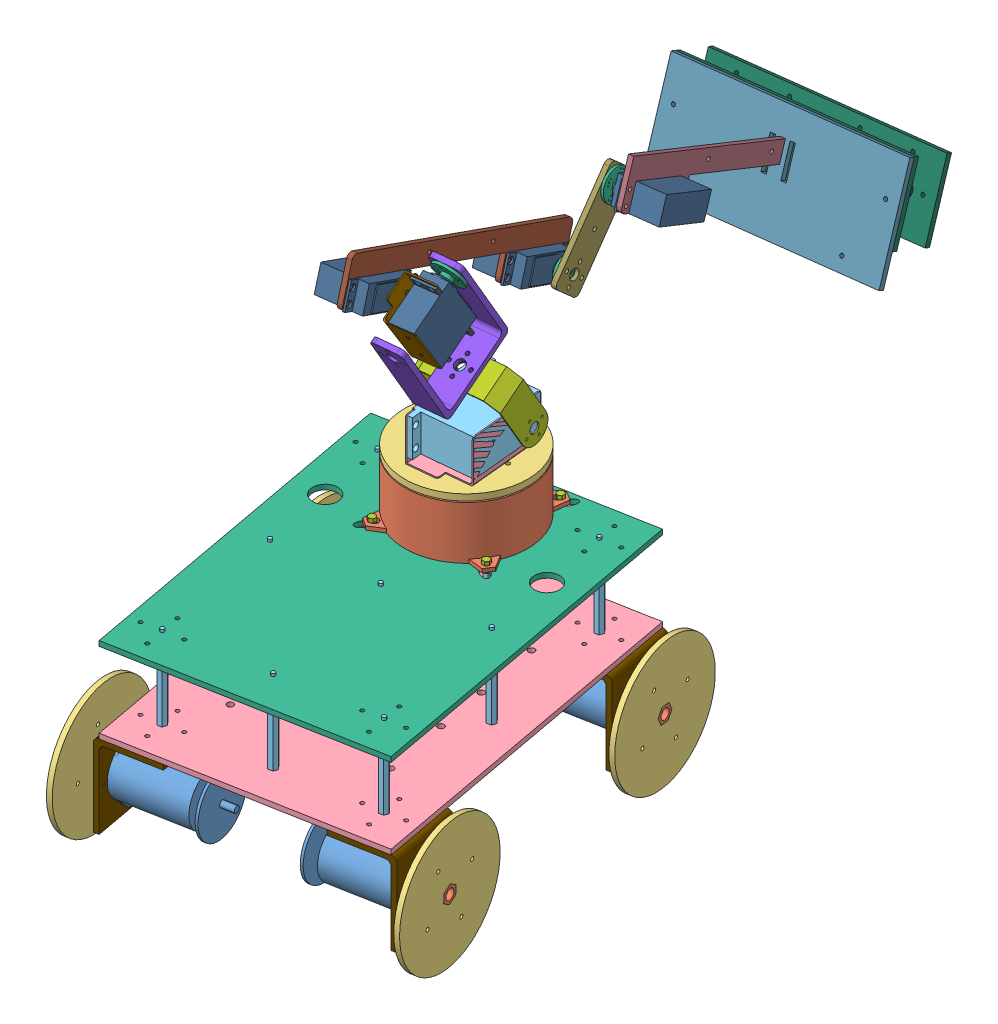
SolidWorks assembly arm 6 DOF + base 1, configuration Default. Lengths in mm.
Overall size (299.4 371.14 566.97).
57 component instances, 25 part files, 169 mates.
Components (placement in the parent):
- hs-422_sws-1: hs-422_sws [Default] at (6.6782 32.5822 43.0057) size (19.81 42.14 58.23)
- base arm-1: base arm [Default] at (19.6982 18.9554 48.4147) x (0.538087 0 -0.842889) z (0.842889 0 0.538087) size (118.01 42 118.01)
- arm base up-1: arm base up [Default] at (19.1744 54.8067 79.8171) x (0.097193 0 0.995266) z (0 1 0) size (98 98 12)
- hs 755 bracket-1: hs 755 bracket [Default] at (-18.8464 89.2206 93.9287) x (-0.995266 0 0.097193) z (-0.097193 0 -0.995266) size (44 34 74)
- hitec hs 755-1: hitec hs 755 [Default] at (45.4604 123.9367 40.3238) x (0 1 0) z (-0.995266 0 0.097193) size (29 74 56.99)
- servo bracket general-1: servo bracket general [Default] at (-12.6703 32.0195 41.7078) x (-0.004258 -0.99904 -0.043598) z (0.995266 0 -0.097193) size (24 24 6)
- u braket joint 1-2-1: u braket joint 1-2 [Default] at (33.276 118.3358 46.1876) x (0.995266 0 -0.097193) z (0.08298 -0.520656 0.849724) size (66 59 24)
- arm junc 2-1: arm junc 2 [Default] at (12.6131 149.17 90.5742) x (0.08298 -0.520656 0.849724) z (0.995266 0 -0.097193) size (64 79 24)
- bracket general hs 645-1: bracket general hs 645 [Default] at (16.6488 206.5636 80.7902) x (-0.08298 0.520656 -0.849724) z (0.016697 -0.851819 -0.52357) size (34 24 57)
- hitec hs 645-1: hitec hs 645 [Default] at (39.0641 204.9316 132.0518) x (-0.016697 0.851819 0.52357) z (-0.08298 0.520656 -0.849724) size (53.34 19.56 42.35)
- servo bracket general-2: servo bracket general [Default] at (69.3008 188.4841 66.8223) x (0.995803 0.010283 -0.090944) z (0.08298 -0.520656 0.849724) size (24 24 6)
- hitec hs 645-2: hitec hs 645 [Default] at (-35.8785 170.8154 49.8227) x (-0.03769 -0.353649 -0.934619) z (0.996411 0.057634 -0.06199) size (53.34 19.56 42.35)
- servo bracket general-3: servo bracket general [Default] at (14.8927 146.1475 127.4607) x (0.084071 -0.588853 0.803856) z (-0.996411 -0.057634 0.06199) size (24 24 6)
- juct c 2 joint-1: juct c 2 joint [Default] at (-16.5608 105.9929 -69.7374) x (-0.03769 -0.353649 -0.934619) z (0.996411 0.057634 -0.06199) size (196.25 35 4)
- hitec hs 645-3: hitec hs 645 [Default] at (-41.1788 121.0832 -81.6089) x (-0.03769 -0.353649 -0.934619) z (0.996411 0.057634 -0.06199) size (53.34 19.56 42.35)
- servo bracket general-4: servo bracket general [Default] at (5.0293 97.459 -76.3462) x (-0.007252 -0.671549 -0.740925) z (-0.996411 -0.057634 0.06199) size (24 24 6)
- arm junct hole 2-1: arm junct hole 2 [Default] at (4.0721 173.6444 -20.9013) x (0.008166 0.6635 0.748131) z (0.996411 0.057634 -0.06199) size (24 80 4)
- hitec hs 645-4: hitec hs 645 [Default] at (49.3983 199.8468 -45.1922) x (0.034818 0.38846 0.920807) z (-0.996411 -0.057634 0.06199) size (53.34 19.56 42.35)
- servo bracket general-5: servo bracket general [Default] at (8.842 133.2278 -46.3345) x (0.083345 -0.795839 0.599745) z (0.996411 0.057634 -0.06199) size (24 24 6)
- juct c 1 joint-1: juct c 1 joint [Default] at (27.8754 177.4322 -42.184) x (0.034818 0.38846 0.920807) z (-0.996411 -0.057634 0.06199) size (140.63 35 4)
- base effector-2: base effector [Default] at (15.0512 145.8778 -201.8232) x (0.996411 0.057634 -0.06199) z (0.034818 0.38846 0.920807) size (180 80 4)
- base webcam fix-1: base webcam fix [Default] at (36.5081 139.2518 -204.1832) x (-0.996411 -0.057634 0.06199) z (-0.034818 -0.38846 -0.920807) size (180 57 4)
- base GM-1: base GM [Default] at (61.7595 88.9126 -188.5139) x (0.996411 0.057634 -0.06199) z (-0.077151 0.919661 -0.38506) size (128 34 20)
- webcam sturdy-2: webcam sturdy [Default] at (35.3697 136.1831 -213.1626) x (-0.996411 -0.057634 0.06199) z (-0.034818 -0.38846 -0.920807) size (79 27 33.5)
- webcam sturdy-3: webcam sturdy [Default] at (-51.318 131.1689 -207.7694) x (-0.996411 -0.057634 0.06199) z (-0.034818 -0.38846 -0.920807) size (79 27 33.5)
- base webcam fix-4: base webcam fix [Default] at (-0.8454 120.559 -226.9219) x (0.996411 0.057634 -0.06199) z (-0.034818 -0.38846 -0.920807) size (180 57 4)
- base junc motor-1: base junc motor [Default] at (-59.8759 -62.795 45.0091) x (0.983449 0 -0.181186) z (0.181186 0 0.983449) size (48 66 56)
- motor dc 1 NISCA-1: motor dc 1 NISCA [Default] at (-81.5979 -135.4054 72.2952) x (0 -1 0) z (0.983449 0 -0.181186) size (54 48 92)
- shaft adapter motor-1: shaft adapter motor [Default] at (-87.0776 -117.0125 64.6288) x (0.115247 -0.771631 0.625543) z (-0.983449 0 0.181186) size (12 13.86 17)
- wheel-1: wheel [Default] at (-110.9174 -68.6438 6.9798) x (-0.178701 -0.165038 -0.969963) z (-0.983449 0 0.181186) size (100 100 4)
- base junc motor-5: base junc motor [Default] at (85.0721 -62.795 18.3046) x (-0.983449 0 0.181186) z (-0.181186 0 -0.983449) size (48 66 56)
- motor dc 1 NISCA-5: motor dc 1 NISCA [Default] at (115.0919 -46.9812 36.058) x (0 1 0) z (-0.983449 0 0.181186) size (54 48 92)
- shaft adapter motor-5: shaft adapter motor [Default] at (111.0741 -111.9911 -7.8266) x (-0.149618 -0.564004 -0.812105) z (0.983449 0 -0.181186) size (12 13.86 17)
- wheel-5: wheel [Default] at (118.4063 -99.8622 -39.7783) x (-0.163308 0.433138 -0.88641) z (0.983449 0 -0.181186) size (100 100 4)
- base junc motor-7: base junc motor [Default] at (123.8459 -62.795 228.7626) x (-0.983449 0 0.181186) z (-0.181186 0 -0.983449) size (48 66 56)
- motor dc 1 NISCA-7: motor dc 1 NISCA [Default] at (145.5678 -135.4054 201.4765) x (0 -1 0) z (-0.983449 0 0.181186) size (54 48 92)
- shaft adapter motor-7: shaft adapter motor [Default] at (149.9905 -69.6302 203.4055) x (-0.097948 0.841282 -0.531649) z (0.983449 0 -0.181186) size (12 13.86 17)
- wheel-7: wheel [Default] at (162.0366 -115.058 174.9636) x (-0.083033 -0.888811 -0.450689) z (-0.983449 0 0.181186) size (100 100 4)
- base junc motor-8: base junc motor [Default] at (-21.1022 -62.795 255.4672) x (0.983449 0 -0.181186) z (0.181186 0 0.983449) size (48 66 56)
- shaft adapter motor-8: shaft adapter motor [Default] at (-45.9025 -101.6896 288.1209) x (0.178209 -0.180542 0.967288) z (-0.983449 0 0.181186) size (12 13.86 17)
- motor dc 1 NISCA-8: motor dc 1 NISCA [Default] at (-51.1219 -46.9812 237.7137) x (0 1 0) z (0.983449 0 -0.181186) size (54 48 92)
- wheel-9: wheel [Default] at (-76.1406 -113.0058 217.8192) x (-0.178209 0.180542 -0.967288) z (0.983449 0 -0.181186) size (100 100 4)
- base odroid down fix-2: base odroid down fix [Default] at (34.2802 -56.1933 60.301) x (0.181186 0 0.983449) z (0 1 0) size (270 200 4)
- spacer 6cm-10: spacer 6cm [Default] at (127.024 7.8067 228.5274) x (0.942285 0 0.334813) z (0 -1 0) size (6 6.93 72)
- spacer 6cm-11: spacer 6cm [Default] at (52.2819 7.8067 242.2975) x (0.942285 0 0.334813) z (0 -1 0) size (6 6.93 72)
- spacer 6cm-12: spacer 6cm [Default] at (-22.4603 7.8067 256.0677) x (0.942285 0 0.334813) z (0 -1 0) size (6 6.93 72)
- spacer 6cm-13: spacer 6cm [Default] at (107.6371 7.8067 123.2984) x (0.942285 0 0.334813) z (0 -1 0) size (6 6.93 72)
- spacer 6cm-14: spacer 6cm [Default] at (32.895 7.8067 137.0685) x (0.942285 0 0.334813) z (0 -1 0) size (6 6.93 72)
- spacer 6cm-15: spacer 6cm [Default] at (-41.8472 7.8067 150.8386) x (0.942285 0 0.334813) z (0 -1 0) size (6 6.93 72)
- spacer 6cm-16: spacer 6cm [Default] at (88.2502 7.8067 18.0694) x (0.942285 0 0.334813) z (0 -1 0) size (6 6.93 72)
- spacer 6cm-17: spacer 6cm [Default] at (13.5081 7.8067 31.8395) x (0.942285 0 0.334813) z (0 -1 0) size (6 6.93 72)
- spacer 6cm-18: spacer 6cm [Default] at (-61.234 7.8067 45.6096) x (0.942285 0 0.334813) z (0 -1 0) size (6 6.93 72)
- base odroid up fix-1: base odroid up fix [Default] at (2.5476 11.8067 66.1472) x (0.181186 0 0.983449) z (0 -1 0) size (270 200 4)
- mur 6mmx3mm-1: mur 6mmx3mm [Default] at (110.3743 14.8067 -4.4574) x (0.999007 0 0.044552) z (0 -1 0) size (5 5.77 9)
- mur 6mmx3mm-2: mur 6mmx3mm [Default] at (74.3344 14.8067 147.0829) x (-0.044552 0 0.999007) z (0 -1 0) size (5 5.77 9)
- mur 6mmx3mm-3: mur 6mmx3mm [Default] at (-77.206 14.8067 111.0429) x (-0.999007 0 -0.044552) z (0 -1 0) size (5 5.77 9)
- mur 6mmx3mm-4: mur 6mmx3mm [Default] at (-41.166 14.8067 -40.4974) x (0.044552 0 -0.999007) z (0 -1 0) size (5 5.77 9)
Mates (geometry in assembly coordinates):
- Coincident2: coincident anti-aligned: plane of hs-422_sws-1 through (26.4902 50.8067 43.0057) normal (0 1 0); plane of base arm-1 through (16.5842 50.8067 53.2927) normal (0 -1 0)
- Parallel4: parallel aligned: plane of hs-422_sws-1 through (26.4902 53.9729 43.0057) normal (0 1 0); plane of base arm-1 through (16.5842 53.8067 53.2927) normal (0 1 0)
- Concentric1: concentric aligned: cylinder of hs-422_sws-1 through (16.5842 34.7173 53.2927) axis (0 1 0) radius 2.8131; cylinder of base arm-1 through (16.5842 50.8067 53.2927) axis (0 1 0) radius 5
- Coincident4: coincident anti-aligned: plane of hs-422_sws-1 through (26.4902 50.8067 43.0057) normal (0 1 0); plane of arm base up-1 through (16.5842 50.8067 53.2927) normal (0 -1 0)
- Parallel5: parallel anti-aligned: plane of hs-422_sws-1 through (26.4902 53.9729 43.0057) normal (0 1 0); plane of arm base up-1 through (16.5842 54.8067 53.2927) normal (0 -1 0)
- Concentric2: concentric aligned: cylinder of hs-422_sws-1 through (16.5842 34.7173 53.2927) axis (0 1 0) radius 2.8131; cylinder of arm base up-1 through (16.5842 50.8067 53.2927) axis (0 1 0) radius 3
- Coincident6: coincident anti-aligned: plane of arm base up-1 through (16.5842 59.8067 53.2927) normal (0 1 0); plane of hs 755 bracket-1 through (42.846 59.8067 13.5521) normal (0 -1 0)
- Concentric3: concentric aligned: cylinder of arm base up-1 through (16.5842 62.8067 53.2927) axis (0 -1 0) radius 4; cylinder of hs 755 bracket-1 through (16.5842 60.8067 53.2927) axis (0 -1 0) radius 4
- Concentric5: concentric anti-aligned: cylinder of arm base up-1 through (15.0291 54.8067 37.3685) axis (0 1 0) radius 1.5; cylinder of hs 755 bracket-1 through (15.0291 60.8067 37.3685) axis (0 -1 0) radius 4
- Concentric6: concentric anti-aligned: cylinder of arm base up-1 through (17.3617 54.8067 61.2549) axis (0 1 0) radius 1.5; cylinder of hs 755 bracket-1 through (17.3617 60.8067 61.2549) axis (0 -1 0) radius 1.5
- Concentric7: concentric anti-aligned: cylinder of arm base up-1 through (8.6221 54.8067 54.0703) axis (0 1 0) radius 1.5; cylinder of hs 755 bracket-1 through (8.6221 60.8067 54.0703) axis (0 -1 0) radius 1.5
- Coincident13: coincident anti-aligned: plane of hs 755 bracket-1 through (0.0496 60.8067 17.7314) normal (0.995266 0 -0.097193); plane of hitec hs 755-1 through (2.664 123.9367 44.5031) normal (-0.995266 0 0.097193)
- Coincident14: coincident anti-aligned: plane of hs 755 bracket-1 through (0.0496 60.8067 17.7314) normal (0.995266 0 -0.097193); plane of hitec hs 755-1 through (2.664 123.9367 44.5031) normal (-0.995266 0 0.097193)
- Concentric9: concentric aligned: cylinder of hs 755 bracket-1 through (0.3412 87.3067 20.7172) axis (-0.995266 0 0.097193) radius 1.5; cylinder of hitec hs 755-1 through (4.3222 87.3067 20.3284) axis (-0.995266 0 0.097193) radius 2.5
- Concentric10: concentric aligned: cylinder of hs 755 bracket-1 through (0.3412 71.3067 20.7172) axis (-0.995266 0 0.097193) radius 1.5; cylinder of hitec hs 755-1 through (4.3222 71.3067 20.3284) axis (-0.995266 0 0.097193) radius 2.5
- Concentric11: concentric aligned: cylinder of hs 755 bracket-1 through (6.9503 71.3067 88.3953) axis (-0.995266 0 0.097193) radius 1.5; cylinder of hitec hs 755-1 through (10.9314 71.3067 88.0065) axis (-0.995266 0 0.097193) radius 2.5
- Concentric12: concentric aligned: cylinder of hs 755 bracket-1 through (6.9503 87.3067 88.3953) axis (-0.995266 0 0.097193) radius 1.5; cylinder of hitec hs 755-1 through (10.9314 87.3067 88.0065) axis (-0.995266 0 0.097193) radius 2.5
- Parallel9: parallel aligned: plane of hs 755 bracket-1 through (-0.9457 93.8067 17.8286) normal (0 1 0); plane of hitec hs 755-1 through (0.7786 93.8067 25.1959) normal (0 1 0)
- Coincident16: coincident anti-aligned: plane of hitec hs 755-1 through (-7.8035 78.8067 40.1006) normal (-0.995266 0 0.097193); plane of servo bracket general-1 through (-7.8035 78.8067 40.1006) normal (0.995266 0 -0.097193)
- Concentric13: concentric anti-aligned: cylinder of hitec hs 755-1 through (-11.7845 78.8067 40.4893) axis (0.995266 0 -0.097193) radius 3; cylinder of servo bracket general-1 through (-7.8035 78.8067 40.1006) axis (-0.995266 0 0.097193) radius 3
- Coincident17: coincident anti-aligned: plane of servo bracket general-1 through (-12.7798 78.8067 40.5865) normal (-0.995266 0 0.097193); plane of u braket joint 1-2-1 through (-9.903 104.2947 70.0452) normal (0.995266 0 -0.097193)
- Concentric14: concentric anti-aligned: cylinder of servo bracket general-1 through (-13.775 78.8067 40.6837) axis (0.995266 0 -0.097193) radius 4; cylinder of u braket joint 1-2-1 through (-12.7798 78.8067 40.5865) axis (-0.995266 0 0.097193) radius 4
- Coincident18: coincident anti-aligned: plane of u braket joint 1-2-1 through (-1.0313 112.6858 74.3204) normal (0.050604 0.853766 0.518191); plane of arm junc 2-1 through (34.462 114.7957 67.3781) normal (-0.050604 -0.853766 -0.518191)
- Concentric15: concentric anti-aligned: cylinder of u braket joint 1-2-1 through (21.8088 118.0799 61.2729) axis (0.050604 0.853766 0.518191) radius 4; cylinder of arm junc 2-1 through (22.0618 122.3488 63.8639) axis (-0.050604 -0.853766 -0.518191) radius 4
- Concentric16: concentric anti-aligned: cylinder of u braket joint 1-2-1 through (21.1449 122.2452 54.4751) axis (0.050604 0.853766 0.518191) radius 1; cylinder of arm junc 2-1 through (21.3979 126.514 57.0661) axis (-0.050604 -0.853766 -0.518191) radius 1.5
- Concentric17: concentric anti-aligned: cylinder of u braket joint 1-2-1 through (22.4726 113.9147 68.0707) axis (0.050604 0.853766 0.518191) radius 1; cylinder of arm junc 2-1 through (22.7256 118.1835 70.6617) axis (-0.050604 -0.853766 -0.518191) radius 1.5
- Coincident19: coincident anti-aligned: plane of bracket general hs 645-1 through (11.9693 148.3874 66.4225) normal (0.08298 -0.520656 0.849724); plane of hitec hs 645-1 through (36.693 219.8094 107.7709) normal (-0.08298 0.520656 -0.849724)
- Coincident20: coincident anti-aligned: plane of bracket general hs 645-1 through (11.9693 148.3874 66.4225) normal (0.08298 -0.520656 0.849724); plane of hitec hs 645-1 through (36.693 219.8094 107.7709) normal (-0.08298 0.520656 -0.849724)
- Concentric18: concentric aligned: cylinder of bracket general hs 645-1 through (29.4536 193.4715 94.1521) axis (-0.08298 0.520656 -0.849724) radius 1.5; cylinder of hitec hs 645-1 through (29.5893 192.6203 95.5414) axis (-0.08298 0.520656 -0.849724) radius 2.5019
- Concentric19: concentric aligned: cylinder of bracket general hs 645-1 through (19.3301 192.886 94.7819) axis (-0.08298 0.520656 -0.849724) radius 1.5; cylinder of hitec hs 645-1 through (19.4658 192.0347 96.1712) axis (-0.08298 0.520656 -0.849724) radius 2.5019
- Concentric20: concentric aligned: cylinder of bracket general hs 645-1 through (30.2595 152.3628 68.8846) axis (-0.08298 0.520656 -0.849724) radius 1.5; cylinder of hitec hs 645-1 through (30.3951 151.5115 70.2739) axis (-0.08298 0.520656 -0.849724) radius 2.5019
- Concentric21: concentric aligned: cylinder of bracket general hs 645-1 through (20.1359 151.7772 69.5144) axis (-0.08298 0.520656 -0.849724) radius 1.5; cylinder of hitec hs 645-1 through (20.2716 150.9259 70.9037) axis (-0.08298 0.520656 -0.849724) radius 2.5019
- Coincident22: coincident anti-aligned: plane of hitec hs 645-1 through (23.0923 189.6731 74.4171) normal (-0.08298 0.520656 -0.849724); plane of servo bracket general-2 through (23.0923 189.6731 74.4171) normal (0.08298 -0.520656 0.849724)
- Concentric22: concentric anti-aligned: cylinder of hitec hs 645-1 through (23.0923 189.6731 74.4171) axis (0.08298 -0.520656 0.849724) radius 2.9972; cylinder of servo bracket general-2 through (23.3413 188.1112 76.9662) axis (-0.08298 0.520656 -0.849724) radius 3
- Lock1: lock: unknown of arm junc 2-1; unknown of servo bracket general-2
- Concentric23: concentric anti-aligned: cylinder of arm junc 2-1 through (22.9264 190.7144 72.7176) axis (-0.08298 0.520656 -0.849724) radius 4; cylinder of servo bracket general-2 through (22.8434 191.2351 71.8679) axis (0.08298 -0.520656 0.849724) radius 4
- Coincident24: coincident anti-aligned: plane of hitec hs 645-2 through (8.9431 176.0872 91.9286) normal (0.996411 0.057634 -0.06199); plane of servo bracket general-3 through (8.9431 176.0872 91.9286) normal (-0.996411 -0.057634 0.06199)
- Concentric24: concentric anti-aligned: cylinder of hitec hs 645-2 through (8.9431 176.0872 91.9286) axis (-0.996411 -0.057634 0.06199) radius 2.9972; cylinder of servo bracket general-3 through (5.9539 175.9143 92.1146) axis (0.996411 0.057634 -0.06199) radius 3
- Lock3: lock: unknown of bracket general hs 645-1; unknown of servo bracket general-3
- Concentric25: concentric aligned: cylinder of bracket general hs 645-1 through (11.9324 176.2601 91.7426) axis (-0.996411 -0.057634 0.06199) radius 4; cylinder of servo bracket general-3 through (11.9324 176.2601 91.7426) axis (-0.996411 -0.057634 0.06199) radius 4
- Coincident30: coincident anti-aligned: plane of hitec hs 645-2 through (-6.0292 195.4786 118.2148) normal (-0.075789 0.933601 -0.350208); plane of juct c 2 joint-1 through (-13.8578 122.0232 -75.9121) normal (0.075789 -0.933601 0.350208)
- Coincident31: coincident anti-aligned: plane of hitec hs 645-2 through (-7.5514 181.1962 80.4693) normal (-0.03769 -0.353649 -0.934619); plane of juct c 2 joint-1 through (-6.2688 165.3963 86.396) normal (0.03769 0.353649 0.934619)
- Coincident32: coincident anti-aligned: plane of hitec hs 645-2 through (-9.0512 172.3672 48.1537) normal (-0.996411 -0.057634 0.06199); plane of juct c 2 joint-1 through (-12.5752 106.2234 -69.9854) normal (0.996411 0.057634 -0.06199)
- Coincident33: coincident anti-aligned: plane of juct c 2 joint-1 through (-12.5752 106.2234 -69.9854) normal (0.996411 0.057634 -0.06199); plane of hitec hs 645-3 through (-14.3514 122.6349 -83.278) normal (-0.996411 -0.057634 0.06199)
- Coincident34: coincident anti-aligned: plane of juct c 2 joint-1 through (-12.5752 106.2234 -69.9854) normal (0.996411 0.057634 -0.06199); plane of hitec hs 645-3 through (-14.3514 122.6349 -83.278) normal (-0.996411 -0.057634 0.06199)
- Coincident35: coincident anti-aligned: plane of juct c 2 joint-1 through (-13.8578 122.0232 -75.9121) normal (0.075789 -0.933601 0.350208); plane of hitec hs 645-3 through (-11.3295 145.7464 -13.2169) normal (-0.075789 0.933601 -0.350208)
- Coincident36: coincident anti-aligned: plane of juct c 2 joint-1 through (-11.569 115.6641 -45.0356) normal (0.03769 0.353649 0.934619); plane of hitec hs 645-3 through (-12.8516 131.4639 -50.9624) normal (-0.03769 -0.353649 -0.934619)
- Coincident37: coincident anti-aligned: plane of hitec hs 645-3 through (3.6429 126.3549 -39.5031) normal (0.996411 0.057634 -0.06199); plane of servo bracket general-4 through (3.6429 126.3549 -39.5031) normal (-0.996411 -0.057634 0.06199)
- Concentric26: concentric anti-aligned: cylinder of hitec hs 645-3 through (3.6429 126.3549 -39.5031) axis (-0.996411 -0.057634 0.06199) radius 2.9972; cylinder of servo bracket general-4 through (0.6537 126.182 -39.3171) axis (0.996411 0.057634 -0.06199) radius 3
- Lock4: lock: unknown of servo bracket general-4; unknown of arm junct hole 2-1
- Concentric27: concentric anti-aligned: cylinder of servo bracket general-4 through (6.6321 126.5278 -39.689) axis (-0.996411 -0.057634 0.06199) radius 4; cylinder of arm junct hole 2-1 through (5.6357 126.4702 -39.627) axis (0.996411 0.057634 -0.06199) radius 4
- Concentric28: concentric anti-aligned: cylinder of hitec hs 645-4 through (6.7219 168.5793 -76.9845) axis (0.996411 0.057634 -0.06199) radius 2.9972; cylinder of servo bracket general-5 through (9.8855 168.7622 -77.1813) axis (-0.996411 -0.057634 0.06199) radius 3
- Coincident40: coincident anti-aligned: plane of hitec hs 645-4 through (9.8855 168.7622 -77.1813) normal (-0.996411 -0.057634 0.06199); plane of servo bracket general-5 through (9.8855 168.7622 -77.1813) normal (0.996411 0.057634 -0.06199)
- Lock5: lock: unknown of arm junct hole 2-1; unknown of servo bracket general-5
- Concentric29: concentric aligned: cylinder of arm junct hole 2-1 through (0.9178 168.2435 -76.6234) axis (0.996411 0.057634 -0.06199) radius 4; cylinder of servo bracket general-5 through (3.907 168.4164 -76.8093) axis (0.996411 0.057634 -0.06199) radius 4
- Coincident42: coincident anti-aligned: plane of hitec hs 645-4 through (20.2485 166.7073 -110.2213) normal (-0.034818 -0.38846 -0.920807); plane of juct c 1 joint-1 through (21.5541 151.1434 -103.7048) normal (0.034818 0.38846 0.920807)
- Coincident43: coincident anti-aligned: plane of hitec hs 645-4 through (21.6546 182.3956 -73.0336) normal (0.034818 0.38846 0.920807); plane of juct c 1 joint-1 through (22.9603 166.8317 -66.517) normal (-0.034818 -0.38846 -0.920807)
- Coincident44: coincident anti-aligned: plane of hitec hs 645-4 through (20.2485 166.7073 -110.2213) normal (-0.077151 0.919661 -0.38506); plane of juct c 1 joint-1 through (22.5841 192.7656 -48.4526) normal (0.077151 -0.919661 0.38506)
- Coincident45: coincident anti-aligned: plane of hitec hs 645-4 through (22.5709 198.295 -43.5232) normal (0.996411 0.057634 -0.06199); plane of juct c 1 joint-1 through (23.8897 177.2017 -41.936) normal (-0.996411 -0.057634 0.06199)
- Coincident54: coincident anti-aligned: plane of juct c 1 joint-1 through (23.8897 177.2017 -41.936) normal (-0.996411 -0.057634 0.06199); plane of base effector-2 through (15.8356 144.8908 -201.4364) normal (0.996411 0.057634 -0.06199)
- Coincident55: coincident anti-aligned: plane of juct c 1 joint-1 through (22.5841 192.7656 -48.4526) normal (0.077151 -0.919661 0.38506); plane of base effector-2 through (17.0237 130.7281 -195.5065) normal (-0.077151 0.919661 -0.38506)
- Coincident57: coincident aligned: plane of juct c 1 joint-1 through (18.3293 115.1642 -188.99) normal (-0.034818 -0.38846 -0.920807); plane of base effector-2 through (15.0512 145.8778 -201.8232) normal (-0.034818 -0.38846 -0.920807)
- Coincident58: coincident anti-aligned: plane of base effector-2 through (15.0512 145.8778 -201.8232) normal (-0.034818 -0.38846 -0.920807); plane of base webcam fix-1 through (36.6473 140.8056 -200.4999) normal (0.034818 0.38846 0.920807)
- Concentric31: concentric aligned: cylinder of base effector-2 through (-61.0895 134.1321 -189.645) axis (-0.034818 -0.38846 -0.920807) radius 1.5; cylinder of base webcam fix-1 through (-61.2287 132.5783 -193.3282) axis (-0.034818 -0.38846 -0.920807) radius 1.5
- Concentric32: concentric aligned: cylinder of base effector-2 through (98.3363 143.3536 -199.5634) axis (-0.034818 -0.38846 -0.920807) radius 1.5; cylinder of base webcam fix-1 through (98.1971 141.7997 -203.2466) axis (-0.034818 -0.38846 -0.920807) radius 1.5
- Coincident59: coincident anti-aligned: plane of base effector-2 through (15.0512 145.8778 -201.8232) normal (-0.034818 -0.38846 -0.920807); plane of base GM-1 through (-32.8918 105.1074 -182.8106) normal (0.034818 0.38846 0.920807)
- Concentric33: concentric aligned: cylinder of base effector-2 through (-36.9631 97.1765 -174.9668) axis (-0.034818 -0.38846 -0.920807) radius 1.5; cylinder of base GM-1 through (-37.1024 95.6226 -178.65) axis (-0.034818 -0.38846 -0.920807) radius 1.5
- Concentric34: concentric aligned: cylinder of base effector-2 through (80.6134 103.9773 -182.2816) axis (-0.034818 -0.38846 -0.920807) radius 1.5; cylinder of base GM-1 through (80.4742 102.4235 -185.9649) axis (-0.034818 -0.38846 -0.920807) radius 1.5
- Tangent3: tangent anti-aligned: plane of base effector-2 through (15.0512 145.8778 -201.8232) normal (-0.034818 -0.38846 -0.920807); cylinder of webcam sturdy-2 through (82.5108 138.9098 -216.0954) axis (0.996411 0.057634 -0.06199) radius 13.5
- Coincident63: coincident anti-aligned: plane of base webcam fix-1 through (40.191 141.0106 -200.7204) normal (0.996411 0.057634 -0.06199); plane of webcam sturdy-2 through (39.6651 136.4315 -213.4298) normal (-0.996411 -0.057634 0.06199)
- Coincident64: coincident anti-aligned: plane of base webcam fix-1 through (83.0367 143.4888 -203.386) normal (-0.996411 -0.057634 0.06199); plane of webcam sturdy-2 through (82.5108 138.9098 -216.0954) normal (0.996411 0.057634 -0.06199)
- Tangent4: tangent anti-aligned: plane of base webcam fix-1 through (37.6331 129.0554 -195.5801) normal (-0.077151 0.919661 -0.38506); cylinder of webcam sturdy-2 through (82.5108 138.9098 -216.0954) axis (0.996411 0.057634 -0.06199) radius 13.5
- Tangent13: tangent anti-aligned: plane of base effector-2 through (15.0512 145.8778 -201.8232) normal (-0.034818 -0.38846 -0.920807); cylinder of webcam sturdy-3 through (-4.177 133.8956 -210.7022) axis (0.996411 0.057634 -0.06199) radius 13.5
- Coincident69: coincident anti-aligned: plane of base webcam fix-1 through (-46.4968 135.9964 -195.3272) normal (0.996411 0.057634 -0.06199); plane of webcam sturdy-3 through (-47.0226 131.4174 -208.0367) normal (-0.996411 -0.057634 0.06199)
- Coincident70: coincident anti-aligned: plane of base webcam fix-1 through (-3.6511 138.4747 -197.9928) normal (-0.996411 -0.057634 0.06199); plane of webcam sturdy-3 through (-4.177 133.8956 -210.7022) normal (0.996411 0.057634 -0.06199)
- Tangent14: tangent anti-aligned: plane of base webcam fix-1 through (37.6331 129.0554 -195.5801) normal (-0.077151 0.919661 -0.38506); cylinder of webcam sturdy-3 through (-4.177 133.8956 -210.7022) axis (0.996411 0.057634 -0.06199) radius 13.5
- Parallel17: parallel anti-aligned: plane of base webcam fix-1 through (36.5081 139.2518 -204.1832) normal (-0.034818 -0.38846 -0.920807); plane of base webcam fix-4 through (-0.7061 122.1128 -223.2387) normal (0.034818 0.38846 0.920807)
- Concentric37: concentric aligned: cylinder of base webcam fix-1 through (-49.3974 152.6692 -202.2513) axis (-0.034818 -0.38846 -0.920807) radius 1.5; cylinder of base webcam fix-4 through (-50.4245 141.2096 -229.4151) axis (-0.034818 -0.38846 -0.920807) radius 1.5
- Concentric38: concentric aligned: cylinder of base webcam fix-1 through (83.1254 160.3345 -210.496) axis (-0.034818 -0.38846 -0.920807) radius 1.5; cylinder of base webcam fix-4 through (82.0982 148.875 -237.6598) axis (-0.034818 -0.38846 -0.920807) radius 1.5
- Coincident74: coincident anti-aligned: plane of webcam sturdy-3 through (-4.177 133.8956 -210.7022) normal (0.996411 0.057634 -0.06199); plane of base webcam fix-4 through (-4.2498 121.9078 -223.0182) normal (-0.996411 -0.057634 0.06199)
- Coincident75: coincident anti-aligned: plane of webcam sturdy-3 through (-47.0226 131.4174 -208.0367) normal (-0.996411 -0.057634 0.06199); plane of base webcam fix-4 through (-47.0955 119.4296 -220.3527) normal (0.996411 0.057634 -0.06199)
- Coincident77: coincident anti-aligned: plane of webcam sturdy-2 through (82.5108 138.9098 -216.0954) normal (0.996411 0.057634 -0.06199); plane of base webcam fix-4 through (82.438 126.922 -228.4114) normal (-0.996411 -0.057634 0.06199)
- Coincident81: coincident aligned: plane of webcam sturdy-2 through (71.8504 130.5643 -233.8916) normal (-0.034818 -0.38846 -0.920807); plane of base webcam fix-4 through (-0.8454 120.559 -226.9219) normal (-0.034818 -0.38846 -0.920807)
- Coincident82: coincident aligned: plane of webcam sturdy-3 through (-14.8374 125.5501 -228.4985) normal (-0.034818 -0.38846 -0.920807); plane of base webcam fix-4 through (-0.8454 120.559 -226.9219) normal (-0.034818 -0.38846 -0.920807)
- Coincident87: coincident anti-aligned: plane of base junc motor-1 through (-90.82 -122.1933 22.2389) normal (0.983449 0 -0.181186); plane of motor dc 1 NISCA-1 through (-85.7468 -91.1933 49.7754) normal (-0.983449 0 0.181186)
- Concentric39: concentric aligned: cylinder of base junc motor-1 through (-89.6806 -91.1933 50.5002) axis (0.983449 0 -0.181186) radius 9.5; cylinder of motor dc 1 NISCA-1 through (-89.6806 -91.1933 50.5002) axis (0.983449 0 -0.181186) radius 9
- Concentric40: concentric anti-aligned: cylinder of base junc motor-1 through (-89.6806 -114.1933 50.5002) axis (0.983449 0 -0.181186) radius 1; cylinder of motor dc 1 NISCA-1 through (-83.7799 -114.1933 49.4131) axis (-0.983449 0 0.181186) radius 1.5
- Concentric41: concentric anti-aligned: cylinder of base junc motor-1 through (-89.6806 -68.1933 50.5002) axis (0.983449 0 -0.181186) radius 1; cylinder of motor dc 1 NISCA-1 through (-83.7799 -68.1933 49.4131) axis (-0.983449 0 0.181186) radius 1.5
- Coincident88: coincident anti-aligned: plane of motor dc 1 NISCA-1 through (-85.5316 -135.4054 73.02) normal (-0.983449 0 0.181186); plane of shaft adapter motor-1 through (-89.6806 -91.1933 50.5002) normal (0.983449 0 -0.181186)
- Concentric42: concentric aligned: cylinder of motor dc 1 NISCA-1 through (-102.4654 -91.1933 52.8556) axis (0.983449 0 -0.181186) radius 2.5; cylinder of shaft adapter motor-1 through (-102.4654 -91.1933 52.8556) axis (0.983449 0 -0.181186) radius 2.5
- Coincident93: coincident anti-aligned: plane of shaft adapter motor-1 through (-106.6064 -84.3601 52.4559) normal (-0.115247 0.771631 -0.625543); plane of wheel-1 through (-102.6726 -84.3601 51.7311) normal (0.115247 -0.771631 0.625543)
- Coincident94: coincident anti-aligned: plane of shaft adapter motor-1 through (-107.3678 -95.6001 48.3228) normal (-0.063454 -0.936669 -0.34442); plane of wheel-1 through (-103.434 -95.6001 47.5981) normal (0.063454 0.936669 0.34442)
- Coincident95: coincident aligned: plane of shaft adapter motor-1 through (-103.7962 -117.0125 67.709) normal (-0.983449 0 0.181186); plane of wheel-1 through (-106.3992 -91.1933 53.5803) normal (-0.983449 0 0.181186)
- Coincident98: coincident anti-aligned: plane of base junc motor-5 through (116.0162 -122.1933 41.0748) normal (-0.983449 0 0.181186); plane of motor dc 1 NISCA-5 through (110.943 -91.1933 13.5383) normal (0.983449 0 -0.181186)
- Concentric46: concentric aligned: cylinder of base junc motor-5 through (114.8768 -91.1933 12.8135) axis (-0.983449 0 0.181186) radius 9.5; cylinder of motor dc 1 NISCA-5 through (114.8768 -91.1933 12.8135) axis (-0.983449 0 0.181186) radius 9
- Parallel18: parallel aligned: plane of base junc motor-5 through (119.95 -122.1933 40.3501) normal (0 -1 0); plane of motor dc 1 NISCA-5 through (113.125 -118.193 36.4204) normal (0 -1 0)
- Concentric47: concentric anti-aligned: cylinder of base junc motor-5 through (114.8768 -114.1933 12.8135) axis (-0.983449 0 0.181186) radius 1; cylinder of motor dc 1 NISCA-5 through (108.9761 -114.1933 13.9006) axis (0.983449 0 -0.181186) radius 1.5
- Concentric48: concentric anti-aligned: cylinder of base junc motor-5 through (114.8768 -68.1933 12.8135) axis (-0.983449 0 0.181186) radius 1; cylinder of motor dc 1 NISCA-5 through (108.9761 -68.1933 13.9006) axis (0.983449 0 -0.181186) radius 1.5
- Coincident100: coincident anti-aligned: plane of motor dc 1 NISCA-5 through (119.0257 -46.9812 35.3333) normal (0.983449 0 -0.181186); plane of shaft adapter motor-5 through (114.8768 -91.1933 12.8135) normal (-0.983449 0 0.181186)
- Concentric49: concentric aligned: cylinder of motor dc 1 NISCA-5 through (127.6616 -91.1933 10.4581) axis (-0.983449 0 0.181186) radius 2.5; cylinder of shaft adapter motor-5 through (127.6616 -91.1933 10.4581) axis (-0.983449 0 0.181186) radius 2.5
- Coincident101: coincident anti-aligned: plane of shaft adapter motor-5 through (132.1391 -84.9487 12.6846) normal (0.149618 0.564004 0.812105); plane of wheel-5 through (128.2053 -84.9487 13.4093) normal (-0.149618 -0.564004 -0.812105)
- Coincident102: coincident anti-aligned: plane of shaft adapter motor-5 through (132.3034 -96.9144 13.5762) normal (0.01369 -0.997142 0.074305); plane of wheel-5 through (128.3696 -96.9144 14.301) normal (-0.01369 0.997142 -0.074305)
- Coincident103: coincident aligned: plane of shaft adapter motor-5 through (127.7928 -111.9911 -10.9068) normal (0.983449 0 -0.181186); plane of wheel-5 through (131.5954 -91.1933 9.7334) normal (0.983449 0 -0.181186)
- Coincident107: coincident anti-aligned: plane of base junc motor-7 through (154.79 -122.1933 251.5329) normal (-0.983449 0 0.181186); plane of motor dc 1 NISCA-7 through (149.7168 -91.1933 223.9963) normal (0.983449 0 -0.181186)
- Concentric52: concentric anti-aligned: cylinder of base junc motor-7 through (153.6506 -114.1933 223.2716) axis (-0.983449 0 0.181186) radius 1; cylinder of motor dc 1 NISCA-7 through (147.7499 -114.1933 224.3587) axis (0.983449 0 -0.181186) radius 1.5
- Parallel19: parallel aligned: plane of base junc motor-7 through (158.7238 -122.1933 250.8081) normal (0 -1 0); plane of motor dc 1 NISCA-7 through (143.6009 -118.193 201.8389) normal (0 -1 0)
- Concentric53: concentric aligned: cylinder of base junc motor-7 through (153.6506 -91.1933 223.2716) axis (-0.983449 0 0.181186) radius 9.5; cylinder of motor dc 1 NISCA-7 through (153.6506 -91.1933 223.2716) axis (-0.983449 0 0.181186) radius 9
- Coincident109: coincident anti-aligned: plane of motor dc 1 NISCA-7 through (149.5016 -135.4054 200.7518) normal (0.983449 0 -0.181186); plane of shaft adapter motor-7 through (153.6506 -91.1933 223.2716) normal (-0.983449 0 0.181186)
- Concentric54: concentric aligned: cylinder of motor dc 1 NISCA-7 through (166.4354 -91.1933 220.9162) axis (-0.983449 0 0.181186) radius 2.5; cylinder of shaft adapter motor-7 through (166.4354 -91.1933 220.9162) axis (-0.983449 0 0.181186) radius 2.5
- Coincident110: coincident anti-aligned: plane of shaft adapter motor-7 through (170.3095 -84.2729 219.8676) normal (0.083033 0.888811 0.450689); plane of wheel-7 through (171.4253 -87.448 225.9235) normal (-0.083033 -0.888811 -0.450689)
- Coincident111: coincident anti-aligned: plane of shaft adapter motor-7 through (169.3131 -94.9387 214.4593) normal (-0.180981 -0.047529 -0.982337); plane of wheel-7 through (169.2535 -88.0183 214.1355) normal (0.180981 0.047529 0.982337)
- Coincident112: coincident aligned: plane of shaft adapter motor-7 through (166.7092 -69.6302 200.3254) normal (0.983449 0 -0.181186); plane of wheel-7 through (170.3692 -91.1933 220.1914) normal (0.983449 0 -0.181186)
- Coincident115: coincident anti-aligned: plane of base junc motor-8 through (-52.0462 -122.1933 232.6969) normal (0.983449 0 -0.181186); plane of motor dc 1 NISCA-8 through (-46.973 -91.1933 260.2335) normal (-0.983449 0 0.181186)
- Concentric57: concentric aligned: cylinder of base junc motor-8 through (-50.9068 -91.1933 260.9582) axis (0.983449 0 -0.181186) radius 9.5; cylinder of motor dc 1 NISCA-8 through (-50.9068 -91.1933 260.9582) axis (0.983449 0 -0.181186) radius 9
- Concentric58: concentric anti-aligned: cylinder of base junc motor-8 through (-50.9068 -114.1933 260.9582) axis (0.983449 0 -0.181186) radius 1; cylinder of motor dc 1 NISCA-8 through (-45.0061 -114.1933 259.8711) axis (-0.983449 0 0.181186) radius 1.5
- Parallel20: parallel aligned: plane of base junc motor-8 through (-55.98 -122.1933 233.4217) normal (0 -1 0); plane of motor dc 1 NISCA-8 through (-49.155 -118.193 237.3514) normal (0 -1 0)
- Concentric59: concentric anti-aligned: cylinder of base junc motor-8 through (-50.9068 -68.1933 260.9582) axis (0.983449 0 -0.181186) radius 1; cylinder of motor dc 1 NISCA-8 through (-45.0061 -68.1933 259.8711) axis (-0.983449 0 0.181186) radius 1.5
- Coincident122: coincident anti-aligned: plane of shaft adapter motor-8 through (-50.9068 -91.1933 260.9582) normal (0.983449 0 -0.181186); plane of motor dc 1 NISCA-8 through (-55.0557 -46.9812 238.4385) normal (-0.983449 0 0.181186)
- Concentric60: concentric aligned: cylinder of shaft adapter motor-8 through (-63.6916 -91.1933 263.3137) axis (0.983449 0 -0.181186) radius 2.5; cylinder of motor dc 1 NISCA-8 through (-63.6916 -91.1933 263.3137) axis (0.983449 0 -0.181186) radius 2.5
- Coincident126: coincident anti-aligned: plane of shaft adapter motor-8 through (-66.6695 -95.6837 269.2271) normal (0.178209 -0.180542 0.967288); plane of wheel-9 through (-66.4429 -88.8694 270.4572) normal (-0.178209 0.180542 -0.967288)
- Coincident127: coincident anti-aligned: plane of shaft adapter motor-8 through (-67.8521 -98.0077 262.8083) normal (0.060775 -0.942065 0.329878); plane of wheel-9 through (-66.6695 -95.6837 269.2271) normal (-0.060775 0.942065 -0.329878)
- Coincident128: coincident aligned: plane of shaft adapter motor-8 through (-62.6211 -101.6896 291.2011) normal (-0.983449 0 0.181186); plane of wheel-9 through (-67.6254 -91.1933 264.0384) normal (-0.983449 0 0.181186)
- Coincident129: coincident anti-aligned: plane of base junc motor-7 through (111.5182 -56.1933 259.5051) normal (0 1 0); plane of base odroid down fix-2 through (34.2802 -56.1933 60.301) normal (0 -1 0)
- Coincident131: coincident aligned: plane of base junc motor-7 through (128.9191 -62.795 256.2992) normal (0.181186 0 0.983449); plane of base odroid down fix-2 through (72.3114 -52.1933 266.7283) normal (0.181186 0 0.983449)
- Concentric61: concentric aligned: cylinder of base junc motor-7 through (128.8318 -56.1933 243.0965) axis (0 -1 0) radius 1.5; cylinder of base odroid down fix-2 through (128.8318 -52.1933 243.0965) axis (0 -1 0) radius 1.5
- Concentric62: concentric aligned: cylinder of base junc motor-7 through (123.3962 -56.1933 213.593) axis (0 -1 0) radius 1.5; cylinder of base odroid down fix-2 through (123.3962 -52.1933 213.593) axis (0 -1 0) radius 1.5
- Coincident132: coincident anti-aligned: plane of base junc motor-8 through (-8.7745 -56.1933 224.7248) normal (0 1 0); plane of base odroid down fix-2 through (34.2802 -56.1933 60.301) normal (0 -1 0)
- Coincident133: coincident aligned: plane of base junc motor-8 through (-16.029 -62.795 283.0037) normal (0.181186 0 0.983449); plane of base odroid down fix-2 through (72.3114 -52.1933 266.7283) normal (0.181186 0 0.983449)
- Concentric63: concentric aligned: cylinder of base junc motor-8 through (-20.6524 -56.1933 270.6368) axis (0 -1 0) radius 1.5; cylinder of base odroid down fix-2 through (-20.6524 -52.1933 270.6368) axis (0 -1 0) radius 1.5
- Concentric64: concentric aligned: cylinder of base junc motor-8 through (-26.088 -56.1933 241.1333) axis (0 -1 0) radius 1.5; cylinder of base odroid down fix-2 through (-26.088 -52.1933 241.1333) axis (0 -1 0) radius 1.5
- Coincident134: coincident anti-aligned: plane of base junc motor-1 through (-47.5482 -56.1933 14.2667) normal (0 1 0); plane of base odroid down fix-2 through (34.2802 -56.1933 60.301) normal (0 -1 0)
- Coincident135: coincident aligned: plane of base junc motor-1 through (-64.9491 -62.795 17.4726) normal (-0.181186 0 -0.983449); plane of base odroid down fix-2 through (23.3912 -52.1933 1.1972) normal (-0.181186 0 -0.983449)
- Concentric65: concentric aligned: cylinder of base junc motor-1 through (-59.4262 -56.1933 60.1787) axis (0 -1 0) radius 1.5; cylinder of base odroid down fix-2 through (-59.4262 -52.1933 60.1787) axis (0 -1 0) radius 1.5
- Concentric66: concentric aligned: cylinder of base junc motor-1 through (-64.8618 -56.1933 30.6752) axis (0 -1 0) radius 1.5; cylinder of base odroid down fix-2 through (-64.8618 -52.1933 30.6752) axis (0 -1 0) radius 1.5
- Coincident136: coincident anti-aligned: plane of base junc motor-5 through (72.7444 -56.1933 49.047) normal (0 1 0); plane of base odroid down fix-2 through (34.2802 -56.1933 60.301) normal (0 -1 0)
- Coincident137: coincident aligned: plane of base junc motor-5 through (79.9989 -62.795 -9.232) normal (-0.181186 0 -0.983449); plane of base odroid down fix-2 through (23.3912 -52.1933 1.1972) normal (-0.181186 0 -0.983449)
- Concentric67: concentric aligned: cylinder of base junc motor-5 through (72.5885 -56.1933 20.6045) axis (0 -1 0) radius 1.5; cylinder of base odroid down fix-2 through (72.5885 -52.1933 20.6045) axis (0 -1 0) radius 1.5
- Concentric68: concentric aligned: cylinder of base junc motor-5 through (102.0919 -56.1933 15.1689) axis (0 -1 0) radius 1.5; cylinder of base odroid down fix-2 through (102.0919 -52.1933 15.1689) axis (0 -1 0) radius 1.5
- Coincident139: coincident anti-aligned: plane of base odroid down fix-2 through (34.2802 -52.1933 60.301) normal (0 1 0); plane of spacer 6cm-10 through (127.024 -52.1933 228.5274) normal (0 -1 0)
- Concentric69: concentric anti-aligned: cylinder of base odroid down fix-2 through (126.114 -52.1933 228.3448) axis (0 -1 0) radius 1.5; cylinder of spacer 6cm-10 through (126.114 -58.1933 228.3448) axis (0 1 0) radius 1.5
- Parallel21: parallel aligned: plane of base odroid down fix-2 through (72.3114 -52.1933 266.7283) normal (0.181186 0 0.983449); plane of spacer 6cm-10 through (128.3609 -52.1933 230.9813) normal (0.181186 0 0.983449)
- Parallel23: parallel aligned: plane of base odroid down fix-2 through (34.2802 -56.1933 60.301) normal (0 -1 0); plane of spacer 6cm-10 through (126.114 -58.1933 228.3448) normal (0 -1 0)
- Coincident143: coincident anti-aligned: plane of spacer 6cm-11 through (52.2819 7.8067 242.2975) normal (0 1 0); plane of base odroid up fix-1 through (2.5476 7.8067 66.1472) normal (0 -1 0)
- Coincident144: coincident aligned: plane of spacer 6cm-17 through (13.5081 7.8067 31.8395) normal (0 1 0); plane of spacer 6cm-16 through (88.2502 7.8067 18.0694) normal (0 1 0)
- Coincident145: coincident aligned: plane of spacer 6cm-17 through (13.5081 7.8067 31.8395) normal (0 1 0); plane of spacer 6cm-18 through (-61.234 7.8067 45.6096) normal (0 1 0)
- Coincident146: coincident aligned: plane of spacer 6cm-17 through (13.5081 7.8067 31.8395) normal (0 1 0); plane of spacer 6cm-15 through (-41.8472 7.8067 150.8386) normal (0 1 0)
- Coincident147: coincident aligned: plane of spacer 6cm-17 through (13.5081 7.8067 31.8395) normal (0 1 0); plane of spacer 6cm-14 through (32.895 7.8067 137.0685) normal (0 1 0)
- Coincident148: coincident aligned: plane of spacer 6cm-17 through (13.5081 7.8067 31.8395) normal (0 1 0); plane of spacer 6cm-13 through (107.6371 7.8067 123.2984) normal (0 1 0)
- Coincident149: coincident aligned: plane of spacer 6cm-17 through (13.5081 7.8067 31.8395) normal (0 1 0); plane of spacer 6cm-12 through (-22.4603 7.8067 256.0677) normal (0 1 0)
- Coincident150: coincident aligned: plane of spacer 6cm-17 through (13.5081 7.8067 31.8395) normal (0 1 0); plane of spacer 6cm-10 through (127.024 7.8067 228.5274) normal (0 1 0)
- Coincident151: coincident anti-aligned: plane of spacer 6cm-17 through (13.5081 7.8067 31.8395) normal (0 1 0); plane of base odroid up fix-1 through (2.5476 7.8067 66.1472) normal (0 -1 0)
- Coincident152: coincident anti-aligned: plane of spacer 6cm-18 through (-61.234 7.8067 45.6096) normal (0 1 0); plane of base odroid up fix-1 through (2.5476 7.8067 66.1472) normal (0 -1 0)
- Coincident153: coincident anti-aligned: plane of spacer 6cm-13 through (107.6371 7.8067 123.2984) normal (0 1 0); plane of base odroid up fix-1 through (2.5476 7.8067 66.1472) normal (0 -1 0)
- Concentric70: concentric anti-aligned: cylinder of spacer 6cm-17 through (12.5981 13.8067 31.6569) axis (0 -1 0) radius 1.5; cylinder of base odroid up fix-1 through (12.5981 7.8067 31.6569) axis (0 1 0) radius 1.5
- Concentric71: concentric anti-aligned: cylinder of spacer 6cm-11 through (51.3719 13.8067 242.1149) axis (0 -1 0) radius 1.5; cylinder of base odroid up fix-1 through (51.3719 7.8067 242.1149) axis (0 1 0) radius 1.5
- Parallel24: parallel aligned: plane of spacer 6cm-11 through (53.6188 -52.1933 244.7514) normal (0.181186 0 0.983449); plane of base odroid up fix-1 through (40.5788 7.8067 272.5746) normal (0.181186 0 0.983449)
- Coincident155: coincident aligned: plane of base odroid down fix-2 through (-79.931 -52.1933 81.3427) normal (-0.983449 0 0.181186); plane of base odroid up fix-1 through (-79.931 7.8067 81.3427) normal (-0.983449 0 0.181186)
- Coincident156: coincident anti-aligned: plane of base arm-1 through (41.3362 11.8067 14.5198) normal (0 -1 0); plane of base odroid up fix-1 through (2.5476 11.8067 66.1472) normal (0 1 0)
- Parallel25: parallel anti-aligned: face of base arm-1; edge_curve of base odroid up fix-1
- Coincident157: coincident anti-aligned: plane of base arm-1 through (13.4701 14.8067 58.1708) normal (0 1 0); plane of mur 6mmx3mm-1 through (110.3743 14.8067 -4.4574) normal (0 -1 0)
- Parallel31: parallel aligned: plane of base arm-1 through (48.3336 14.8067 3.5587) normal (0.538087 0 -0.842889); plane of mur 6mmx3mm-1 through (48.8371 17.8067 6.347) normal (0.538087 0 -0.842889)
- Tangent19: tangent: edge_curve of base arm-1; cylinder of mur 6mmx3mm-1 through (46.2753 8.8067 7.6775) axis (0 1 0) radius 1.5
- Tangent20: tangent: edge_curve of base odroid up fix-1; cylinder of mur 6mmx3mm-1 through (46.2753 8.8067 7.6775) axis (0 1 0) radius 1.5
- Tangent21: tangent: edge_curve of base odroid up fix-1; cylinder of mur 6mmx3mm-4 through (-29.031 8.8067 23.6016) axis (0 1 0) radius 1.5
- Parallel38: parallel aligned: edge_curve of base odroid up fix-1; cylinder of mur 6mmx3mm-3 through (-13.1069 8.8067 98.9079) axis (0 1 0) radius 1.5
- Tangent24: tangent: edge_curve of base odroid up fix-1; cylinder of mur 6mmx3mm-3 through (-13.1069 8.8067 98.9079) axis (0 1 0) radius 1.5
- Parallel43: parallel aligned: plane of base odroid up fix-1 through (2.5476 7.8067 66.1472) normal (0 -1 0); plane of mur 6mmx3mm-4 through (-29.031 8.8067 23.6016) normal (0 -1 0)
- Parallel46: parallel aligned: plane of base odroid up fix-1 through (2.5476 7.8067 66.1472) normal (0 -1 0); plane of mur 6mmx3mm-2 through (62.1994 8.8067 82.9838) normal (0 -1 0)
- Lock6: lock: unknown of base arm-1; unknown of base odroid up fix-1
